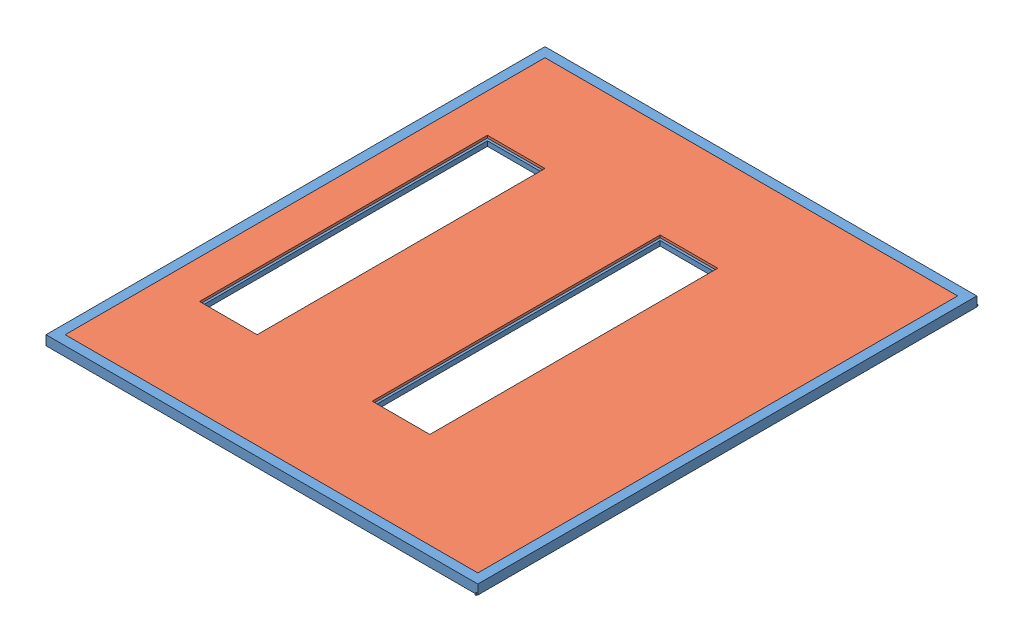
SolidWorks assembly FARWALL_ASSEMBLY, configuration Default. Lengths in mm.
Overall size (2286 50.8 2654.3).
2 component instances, 2 part files, 3 mates.
Components (placement in the parent):
- FARWALL_FRAME-1: FARWALL_FRAME [Default] at (1083.2626 1176.9319 2079.8088) size (2286 50.8 2654.3)
- FARWALL_INSULATION_99X86X2-2: FARWALL_INSULATION_99X86X2 [Default] at (1083.2626 1151.5319 2079.8088) size (2184.4 50.8 2540)
Mates (geometry in assembly coordinates):
- Coincident1: coincident anti-aligned: plane of FARWALL_FRAME-1 through (2175.4626 1202.3319 756.3688) normal (-1 0 0); plane of FARWALL_INSULATION_99X86X2-2 through (2175.4626 1202.3319 809.8088) normal (1 0 0)
- Coincident2: coincident anti-aligned: plane of FARWALL_FRAME-1 through (2228.9026 1202.3319 3349.8088) normal (0 0 -1); plane of FARWALL_INSULATION_99X86X2-2 through (-8.9374 1202.3319 3349.8088) normal (0 0 1)
- Coincident3: coincident aligned: plane of FARWALL_FRAME-1 through (-62.3774 1151.5319 809.8088) normal (0 -1 0); plane of FARWALL_INSULATION_99X86X2-2 through (1083.2626 1151.5319 2079.8088) normal (0 -1 0)
